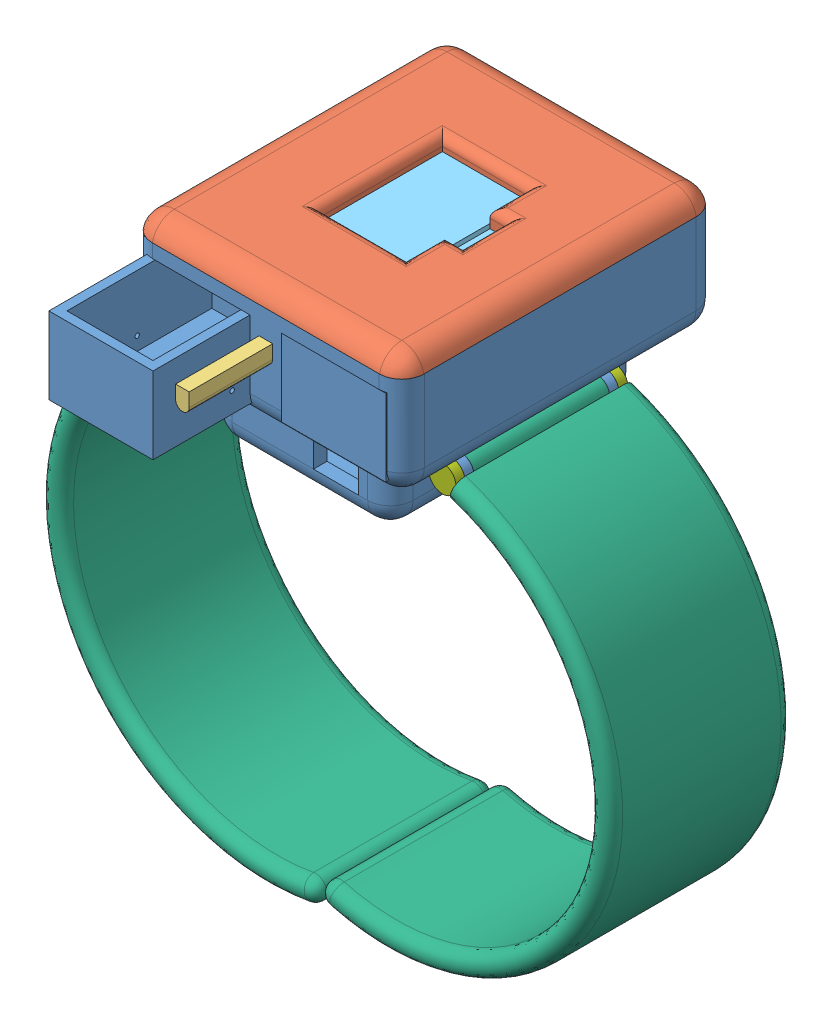
SolidWorks assembly Complete Dispenser structure, configuration Default. Lengths in mm.
Overall size (149.63 141.93 91.45).
43 component instances, 25 part files, 35 mates.
Components (placement in the parent):
- Casing-1: Casing [Default] at (13.487 14.6794 43.0902) size (60 38 70)
- Battery (mini)-1: Battery (mini) [Default] at (1.487 15.5006 28.5902) x (0 0 1) z (-1 0 0) size (20 4.4 10)
- arduino nano part-1: arduino nano part [Default] at (13.867 16.4794 22.4102) x (0 0 1) z (-1 0 0) size (45 7.28 18)
  - nano-board-1: nano-board [Default] at origin size (43.2 4.6 18)
  - atmega328-1: atmega328 [Default] at (23.85 1.75 -7.62) x (-0.707107 0 0.707107) z (-0.707107 0 -0.707107) size (10 1.11 10)
  - ftdi FT232rl-1: ftdi FT232rl [Default] at (29.05 0 -7.67) x (0 0 -1) z (-1 0 0) size (9.25 1.9 10.2)
  - smt_resistor222-1: smt_resistor222 [Default] at (21.86 0 -5.8) x (0 0 -1) z (-1 0 0) size (1.7 0.6 3.8)
  - smt_resistor222-2: smt_resistor222 [Default] at (21.86 0 -9) x (0 0 -1) z (-1 0 0) size (1.7 0.6 3.8)
  - smt_resistor222-3: smt_resistor222 [Default] at (36.75 0 -7.6) x (0 0 -1) z (-1 0 0) size (1.7 0.6 3.8)
  - smt_resistor222-4: smt_resistor222 [Default] at (36.75 0 -12) x (0 0 -1) z (-1 0 0) size (1.7 0.6 3.8)
  - smt_resistor222-5: smt_resistor222 [Default] at (8.2 0 -2.6) x (0 0 -1) z (-1 0 0) size (1.7 0.6 3.8)
  - led-1: led [Default] at (10.4 1.6 -2.8) size (4 0.9 1.55)
  - led-2: led [Default] at (10.4 1.6 -5.55) size (4 0.9 1.55)
  - led-3: led [Default] at (10.4 1.6 -12.5) size (4 0.9 1.55)
  - led-4: led [Default] at (10.4 1.6 -9.05) size (4 0.9 1.55)
  - 16mhz crystal - measured-1: 16mhz crystal - measured [Default] at (18.5113 1.6 -3.5541) x (0.707107 0 0.707107) z (-0.707107 0 0.707107) size (3.4 0.8 2)
  - MINIUSBSHELL-1: MINIUSBSHELL [Default] at (38.98 1.65 -7.62) x (0 0 1) z (-1 0 0) size (10.9 3.85 9.41)
  - MINIUSBCORE-1: MINIUSBCORE [Default] at (32.28 1.65 -7.62) x (0 0 -1) z (1 0 0) size (7.7 4.5 8.2)
  - MINI USB CONTACT-1: MINI USB CONTACT [Default] at (33.28 1.65 -9.22) x (0 0 -1) z (1 0 0) size (0.53 2.55 9.41)
  - MINI USB CONTACT-2: MINI USB CONTACT [Default] at (33.28 1.65 -8.42) x (0 0 -1) z (1 0 0) size (0.53 2.55 9.41)
  - MINI USB CONTACT-3: MINI USB CONTACT [Default] at (33.28 1.65 -7.62) x (0 0 -1) z (1 0 0) size (0.53 2.55 9.41)
  - MINI USB CONTACT-4: MINI USB CONTACT [Default] at (33.28 1.65 -6.82) x (0 0 -1) z (1 0 0) size (0.53 2.55 9.41)
  - MINI USB CONTACT-5: MINI USB CONTACT [Default] at (33.28 1.65 -6.02) x (0 0 -1) z (1 0 0) size (0.53 2.55 9.41)
  - cap106C-1: cap106C [Default] at (37.2 0 -3.3) x (0 0 1) z (1 0 0) size (1.7 1.81 4)
  - cap106C-2: cap106C [Default] at (7.9 0 -5.6) x (0 0 -1) z (-1 0 0) size (1.7 1.81 4)
  - reset core-1: reset core [Default] at (15.25 1.6 -8.05) x (0 0 -1) z (1 0 0) size (5.2 2.15 2.8)
  - reset shell-1: reset shell [Default] at (15.25 3.25 -8.05) size (3 1.65 4)
  - nano - reg-1: nano - reg [Default] at (6.1 0 -10.16) x (0 0 -1) z (-1 0 0) size (6.5 1.69 8.3)
  - NANO DIODE-1: NANO DIODE [Default] at (11.43 0 -4.2) x (0 0 1) z (1 0 0) size (4.92 1.38 1.7)
  - 189 RESISTOR PACK-1: 189 RESISTOR PACK [Default] at (15.75 0 -10.85) x (0 0 1) z (1 0 0) size (3.2 0.51 3)
  - 102 RESISTOR PACK-1: 102 RESISTOR PACK [Default] at (15.75 0 -5.2) x (0 0 1) z (1 0 0) size (3.2 0.51 3)
- dispenser sections-1: dispenser sections [Default] at (-1.513 38.1794 29.5372) size (23 17 70)
- dispenser sections-2: dispenser sections [Default] at (28.487 38.1794 8.0902) size (23 17 70)
- Cover-1: Cover [Default] at (13.487 49.6794 43.0902) x (0 0 -1) z (1 0 0) size (70 7 60)
- shaft-1: shaft [Default] at (13.487 32.6794 16.0902) size (8 4.5 35)
- actuator2-2: actuator2 [Default] at (13.487 35.6794 11.0902) size (7 12 22)
- actuator2-3: actuator2 [Default] at (13.487 43.6794 75.0902) x (-1 0 0) z (0 0 -1) size (7 12 22)
- shaft-2: shaft [Default] at (13.487 40.6794 91.5372) x (-1 0 0) z (0 0 -1) size (8 4.5 35)
- OLED_27x27_r2-1: OLED_27x27_r2 [Default] at (13.487 48.6794 43.0902) x (0 0 1) z (-1 0 0) size (27.3 2.82 27.3)
- strap_v2-1: strap_v2 [Default] at (24.805 -25.4017 63.0902) x (0 0 -1) z (0.306353 0.951918 0) size (40 56 100.38)
- strap_v2-2: strap_v2 [Default] at (-1.5015 -26.1794 23.0902) x (0 0 1) z (-0.230326 0.973114 0) size (40 56 100.38)
- pin-2: pin [Default] at (-9.513 20.6794 26.0902) size (6 6 38)
- pin-3: pin [Default] at (36.487 20.6794 26.0902) size (6 6 38)
Mates (geometry in assembly coordinates):
- Coincident1: coincident anti-aligned: plane of Casing-1 through (-3.513 26.6794 18.5902) normal (0 0 1); plane of arduino nano part-1/nano-board-1 through (12.487 16.4794 18.5902) normal (0 0 -1)
- Coincident2: coincident anti-aligned: plane of Casing-1 through (30.487 26.6794 67.5902) normal (-1 0 0); plane of arduino nano part-1/nano-board-1 through (30.487 16.4794 18.5902) normal (1 0 0)
- Coincident3: coincident anti-aligned: plane of Casing-1 through (13.487 14.6794 43.0902) normal (0 1 0); plane of arduino nano part-1/cap106C-1 through (18.017 14.6794 61.2852) normal (0 -1 0)
- Coincident5: coincident anti-aligned: plane of Casing-1 through (-3.513 26.6794 67.5902) normal (1 0 0); plane of Battery (mini)-1 through (-3.513 19.9006 18.5902) normal (-1 0 0)
- Coincident6: coincident anti-aligned: plane of Casing-1 through (-3.513 26.6794 18.5902) normal (0 0 1); plane of Battery (mini)-1 through (-3.513 19.9006 18.5902) normal (0 0 -1)
- Coincident7: coincident anti-aligned: plane of Casing-1 through (9.987 14.6794 112.0902) normal (-1 0 0); plane of dispenser sections-1 through (9.987 38.1794 99.5372) normal (1 0 0)
- Coincident8: coincident anti-aligned: plane of Casing-1 through (13.487 29.6794 43.0902) normal (0 1 0); plane of dispenser sections-1 through (-1.513 29.6794 99.5372) normal (0 -1 0)
- Coincident11: coincident anti-aligned: plane of Casing-1 through (39.987 14.6794 112.0902) normal (-1 0 0); plane of dispenser sections-2 through (39.987 38.1794 78.0902) normal (1 0 0)
- Coincident12: coincident anti-aligned: plane of Casing-1 through (13.487 29.6794 43.0902) normal (0 1 0); plane of dispenser sections-2 through (28.487 29.6794 78.0902) normal (0 -1 0)
- Coincident18: coincident anti-aligned: plane of Casing-1 through (-13.513 49.6794 75.0902) normal (1 0 0); plane of Cover-1 through (-13.513 46.6794 75.0902) normal (-1 0 0)
- Coincident19: coincident anti-aligned: plane of Casing-1 through (-13.513 49.6794 75.0902) normal (0 0 -1); plane of Cover-1 through (-13.513 46.6794 75.0902) normal (0 0 1)
- Coincident21: coincident anti-aligned: plane of shaft-1 through (11.987 35.6794 46.0902) normal (-1 0 0); plane of actuator2-2 through (11.987 35.6794 13.0902) normal (1 0 0)
- Concentric1: concentric anti-aligned: cylinder of shaft-1 through (13.487 32.6794 46.0902) axis (0 0 -1) radius 1.5; cylinder of actuator2-2 through (13.487 32.6794 13.0902) axis (0 0 1) radius 1.5
- Coincident22: coincident anti-aligned: plane of Casing-1 through (-13.513 49.6794 11.0902) normal (0 0 1); plane of actuator2-2 through (13.487 35.6794 11.0902) normal (0 0 -1)
- Coincident23: coincident anti-aligned: plane of dispenser sections-2 through (16.987 38.1794 78.0902) normal (-1 0 0); plane of actuator2-2 through (16.987 29.6794 23.0902) normal (1 0 0)
- Coincident24: coincident anti-aligned: plane of Casing-1 through (13.487 29.6794 43.0902) normal (0 1 0); plane of actuator2-2 through (9.987 29.6794 23.0902) normal (0 -1 0)
- Concentric2: concentric anti-aligned: cylinder of dispenser sections-2 through (-17.013 34.1794 43.0902) axis (1 0 0) radius 0.5; cylinder of shaft-1 through (19.987 34.1794 43.0902) axis (-1 0 0) radius 0.5
- Coincident27: coincident anti-aligned: plane of Casing-1 through (-13.513 49.6794 75.0902) normal (0 0 -1); plane of actuator2-3 through (13.487 43.6794 75.0902) normal (0 0 1)
- Coincident28: coincident anti-aligned: plane of dispenser sections-2 through (16.987 38.1794 78.0902) normal (-1 0 0); plane of actuator2-3 through (16.987 37.6794 63.0902) normal (1 0 0)
- Coincident30: coincident aligned: plane of Casing-1 through (13.487 49.6794 43.0902) normal (0 1 0); plane of actuator2-3 through (16.987 49.6794 63.0902) normal (0 1 0)
- Coincident31: coincident anti-aligned: plane of actuator2-3 through (14.987 43.6794 73.0902) normal (-1 0 0); plane of shaft-2 through (14.987 43.6794 61.5372) normal (1 0 0)
- Concentric4: concentric anti-aligned: cylinder of actuator2-3 through (13.487 40.6794 73.0902) axis (0 0 -1) radius 1.5; cylinder of shaft-2 through (13.487 40.6794 61.5372) axis (0 0 1) radius 1.5
- Concentric5: concentric aligned: cylinder of dispenser sections-1 through (-47.013 42.1794 64.5372) axis (1 0 0) radius 0.5; cylinder of shaft-2 through (6.987 42.1794 64.5372) axis (1 0 0) radius 0.5
- Coincident32: coincident anti-aligned: plane of Cover-1 through (13.487 43.6794 29.5902) normal (0 0 1); plane of OLED_27x27_r2-1 through (3.987 50.6794 29.5902) normal (0 0 -1)
- Coincident33: coincident anti-aligned: plane of Cover-1 through (22.987 43.6794 43.0902) normal (-1 0 0); plane of OLED_27x27_r2-1 through (22.987 50.6794 29.5902) normal (1 0 0)
- Coincident34: coincident anti-aligned: plane of Cover-1 through (13.487 49.6794 43.0902) normal (0 -1 0); plane of OLED_27x27_r2-1 through (1.837 49.6794 54.7402) normal (0 1 0)
- Coincident35: coincident anti-aligned: plane of Casing-1 through (13.487 49.6794 43.0902) normal (0 1 0); plane of Cover-1 through (13.487 49.6794 43.0902) normal (0 -1 0)
- Concentric6: concentric anti-aligned: cylinder of Casing-1 through (-9.513 20.6794 77.0902) axis (0 0 -1) radius 2; cylinder of strap_v2-2 through (-9.513 20.6794 28.0902) axis (0 0 1) radius 2
- Coincident36: coincident anti-aligned: plane of Casing-1 through (-12.513 14.6794 28.0902) normal (0 0 1); plane of strap_v2-2 through (-9.513 20.6794 28.0902) normal (0 0 -1)
- Concentric7: concentric aligned: cylinder of Casing-1 through (36.487 20.6794 77.0902) axis (0 0 -1) radius 2; cylinder of strap_v2-1 through (36.487 20.6794 58.0902) axis (0 0 -1) radius 2
- Coincident37: coincident anti-aligned: plane of Casing-1 through (39.487 14.6794 58.0902) normal (0 0 -1); plane of strap_v2-1 through (36.487 20.6794 58.0902) normal (0 0 1)
- Concentric8: concentric anti-aligned: cylinder of strap_v2-2 through (-9.513 20.6794 28.0902) axis (0 0 1) radius 2; cylinder of pin-2 through (-9.513 20.6794 60.0902) axis (0 0 -1) radius 2
- Coincident38: coincident anti-aligned: plane of Casing-1 through (-12.513 14.6794 60.0902) normal (0 0 1); plane of pin-2 through (-9.513 20.6794 60.0902) normal (0 0 -1)
- Concentric9: concentric aligned: cylinder of strap_v2-1 through (36.487 20.6794 58.0902) axis (0 0 -1) radius 2; cylinder of pin-3 through (36.487 20.6794 60.0902) axis (0 0 -1) radius 2
- Coincident39: coincident anti-aligned: plane of Casing-1 through (39.487 14.6794 60.0902) normal (0 0 1); plane of pin-3 through (36.487 20.6794 60.0902) normal (0 0 -1)
